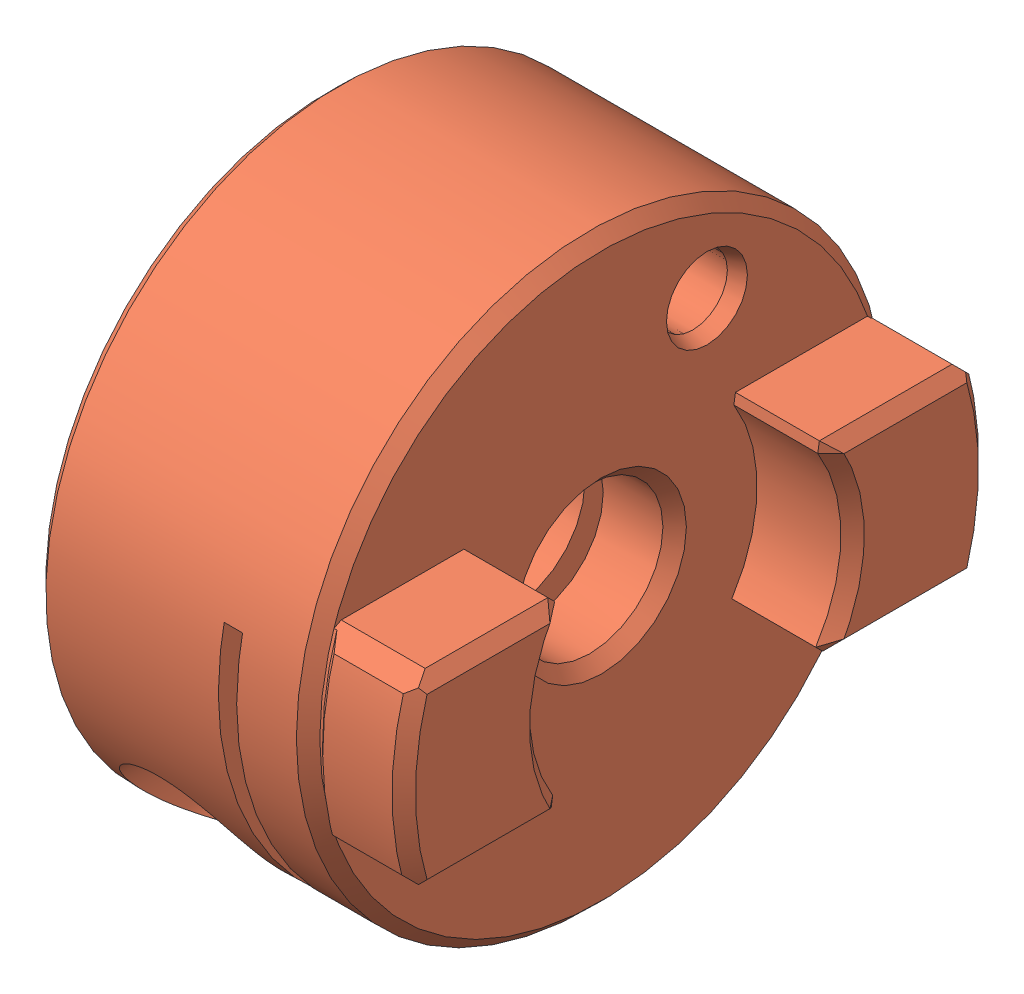
SolidWorks assembly GE-19242, configuration Default. Lengths in mm.
Overall size (16 25.4 25.4).
2 component instances, 2 part files, 0 mates.
Components (placement in the parent):
- Ruland_metric socket head cap screws 1_cfm3_10-1: Ruland_metric socket head cap screws 1_cfm3_10 [Default] at (8.255 -22.7076 6.731) size (5.5 5.5 13)
- Ruland_oct-moct_oct16-4-a-d-1: Ruland_oct-moct_oct16-4-a-d [Default] at (4.2672 -13.9446 3.7211) size (16 25.4 25.4)
